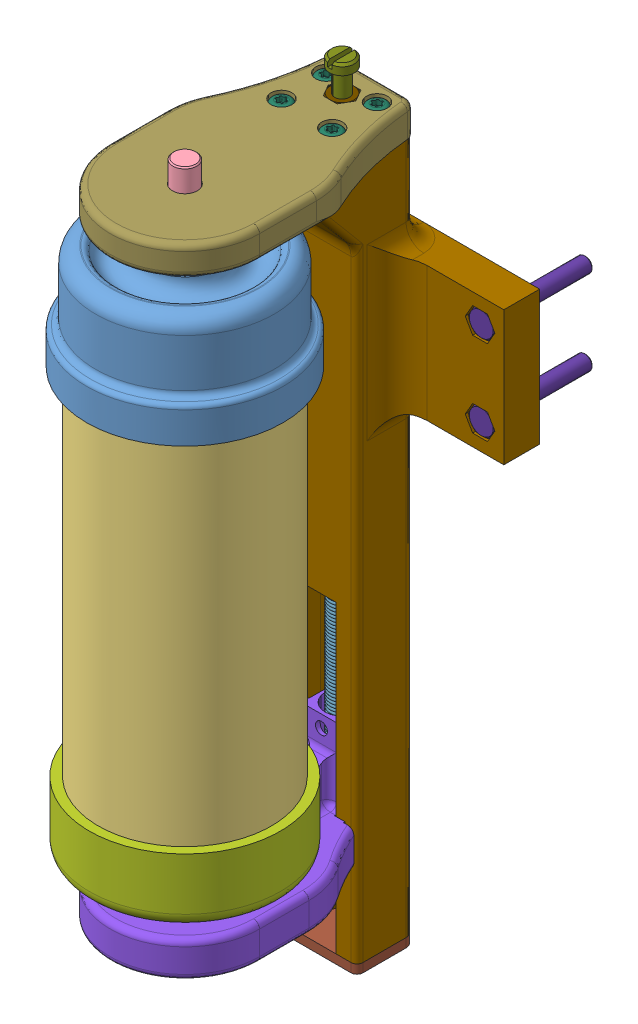
SolidWorks assembly AssemV-Chiller, configuration Default. Lengths in mm.
Overall size (100 255.81 129.09).
29 component instances, 18 part files, 65 mates.
Components (placement in the parent):
- Top holder of can-1: Top holder of can [Default] at (36.1197 55.3594 37.5996) x (-1 0 0) z (0 0 1) size (65.8 35 65.8)
- 250 ml CAN-1: 250 ml CAN [Default] at (36.1197 -108.6231 37.5996) x (0.908209 0 -0.418517) z (0.418517 0 0.908209) size (53.3 134.4 54.81)
- 330 ml CAN-1: 330 ml CAN [Default] at (36.1197 -101.7316 37.5996) x (0 0 1) z (-1 0 0) size (58 146 58)
- Screw M8x30-1: Screw M8x30 [Default] at (36.1197 60.7594 37.5996) x (-1 0 0) z (0 0 1) size (15.01 35.5 13)
- Washer M8_ISO 7090-1: Washer M8_ISO 7090 [Default] at (36.1197 60.7594 37.5996) x (0.773857 0 0.63336) z (-0.63336 0 0.773857) size (16 1.6 16)
- Screw nut M8-3: Screw nut M8 [Default] at (36.1197 66.9594 37.5996) x (0.505771 0 -0.862668) z (0 1 0) size (15.01 13 6.5)
- Washer M8_ISO 7090-3: Washer M8_ISO 7090 [Default] at (36.1197 66.9594 37.5996) x (0.994262 0 -0.106973) z (-0.106973 0 -0.994262) size (16 1.6 16)
- Bottom holder of can-1: Bottom holder of can [Default] at (36.1197 -110.6018 37.5996) x (0 0 -1) z (1 0 0) size (64 22 64)
- Screw M8x30-2: Screw M8x30 [Default] at (36.1197 -105.0018 37.5999) x (0.840809 0 -0.541331) z (0.541331 0 0.840809) size (15.01 35.5 13)
- Screw nut M8-4: Screw nut M8 [Default] at (36.1197 -118.7018 37.5999) x (0.505771 0 -0.862668) z (0 1 0) size (15.01 13 6.5)
- Washer M8_ISO 7090-4: Washer M8_ISO 7090 [Default] at (36.1197 -105.0018 37.5996) x (0.987196 0 -0.159509) z (-0.159509 0 -0.987196) size (16 1.6 16)
- Washer M8_ISO 7090-5: Washer M8_ISO 7090 [Default] at (36.1197 -110.6018 37.5999) x (0.987196 0 -0.159509) z (-0.159509 0 -0.987196) size (16 1.6 16)
- Spring holder_Bottom-1: Spring holder_Bottom [Default] at (36.1197 -130.5018 25.0999) x (0 0 1) z (0 1 0) size (84.36 50 42)
- Circular tube-1: Circular tube [Default] at (36.1197 -143.3406 -15.0604) size (100 231.6 45.4)
- Bearing 608-1: Bearing 608 [Default] at (36.1197 -122.2018 37.5999) x (0 1 0) z (0.985159 0 -0.171644) size (7 22 22)
- Screw nut M8-5: Screw nut M8 [Default] at (36.1197 -137.0018 37.5999) x (0.505771 0 -0.862668) z (0 1 0) size (15.01 13 6.5)
- Cover of circular tube bottom-1: Cover of circular tube bottom [Default] at (36.1197 -161.3406 -15.5604) x (0 0 -1) z (1 0 0) size (19.4 3 28.4)
- Holder of top bearing-1: Holder of top bearing [Default] at (36.1197 83.2594 25.0996) x (0 0 1) z (0 -1 0) size (87.86 50 10)
- Bearing 608-2: Bearing 608 [Default] at (36.1197 76.9594 37.5996) x (0 1 0) z (0.985159 0 -0.171644) size (7 22 22)
- 200 ml CAN-1: 200 ml CAN [Default] at (36.1197 -101.2229 37.5996) size (53.3 111.5 54.81)
- Tension spring-2: Tension spring [Default] at (36.1197 -103.0957 -14.702) x (1 0 0) z (0 1 0) size (8.62 9.93 100.8)
- 96817A522_THREAD-FORMING SCREW FOR THIN PLASTIC-1: 96817A522_THREAD-FORMING SCREW FOR THIN PLASTIC [96817A522] at (44.6197 79.8594 -18.2604) x (-0.165448 0 -0.986219) z (0 1 0) size (6.82 6.82 17.11)
- 96817A522_THREAD-FORMING SCREW FOR THIN PLASTIC-2: 96817A522_THREAD-FORMING SCREW FOR THIN PLASTIC [96817A522] at (44.6197 79.8594 -3.2604) x (0.912516 0 0.409041) z (0 1 0) size (6.82 6.82 17.11)
- 96817A522_THREAD-FORMING SCREW FOR THIN PLASTIC-3: 96817A522_THREAD-FORMING SCREW FOR THIN PLASTIC [96817A522] at (27.6197 79.8594 -3.2604) x (0.988371 0 0.152064) z (0 1 0) size (6.82 6.82 17.11)
- 96817A522_THREAD-FORMING SCREW FOR THIN PLASTIC-4: 96817A522_THREAD-FORMING SCREW FOR THIN PLASTIC [96817A522] at (27.6197 79.8594 -18.2604) x (1 0 0) z (0 1 0) size (6.82 6.82 17.11)
- Screw M5x50-1: Screw M5x50 [Default] at (36.1197 41.173 -15.0604) size (8.3 53.3 8.3)
- HEX screw M5X40-2: HEX screw M5X40 [Default] at (78.1545 34.9594 -23.2604) x (1 0 0) z (0 -1 0) size (9.24 35.1 8)
- HEX screw M5X40-3: HEX screw M5X40 [Default] at (78.1545 6.5594 -23.2604) x (1 0 0) z (0 -1 0) size (9.24 35.1 8)
- Nut M5-1: Nut M5 [Default] at (36.1197 79.2594 -15.0604) size (9.24 4 8)
Mates (geometry in assembly coordinates):
- Concentric1: concentric anti-aligned: cylinder of Top holder of can-1 through (36.1197 30.3594 37.5996) axis (0 1 0) radius 32.9; cylinder of 330 ml CAN-1 through (36.1197 -101.7316 37.5996) axis (0 -1 0) radius 29
- Concentric2: concentric anti-aligned: cylinder of Top holder of can-1 through (36.1197 30.3594 37.5996) axis (0 1 0) radius 32.9; cylinder of 250 ml CAN-1 through (36.1197 -108.6231 37.5996) axis (0 -1 0) radius 26.65
- Coincident1: coincident anti-aligned: plane of Top holder of can-1 through (36.1197 62.3594 37.5996) normal (0 -1 0); plane of Washer M8_ISO 7090-1 through (36.1197 62.3594 37.5996) normal (0 1 0)
- Concentric3: concentric aligned: cylinder of Top holder of can-1 through (36.1197 65.3594 37.5996) axis (0 -1 0) radius 4.1; cylinder of Washer M8_ISO 7090-1 through (36.1197 62.3594 37.5996) axis (0 -1 0) radius 4.2
- Coincident2: coincident anti-aligned: plane of Screw M8x30-1 through (36.1197 60.7594 37.5996) normal (0 1 0); plane of Washer M8_ISO 7090-1 through (36.1197 60.7594 37.5996) normal (0 -1 0)
- Concentric4: concentric aligned: cylinder of Top holder of can-1 through (36.1197 65.3594 37.5996) axis (0 -1 0) radius 4.1; cylinder of Screw M8x30-1 through (36.1197 90.7594 37.5996) axis (0 -1 0) radius 4
- Concentric5: concentric anti-aligned: cylinder of Screw M8x30-1 through (36.1197 90.7594 37.5996) axis (0 -1 0) radius 4; cylinder of Screw nut M8-3 through (36.1197 73.4594 37.5996) axis (0 1 0) radius 3.4
- Concentric61: concentric anti-aligned: cylinder of Screw M8x30-1 through (36.1197 90.7594 37.5996) axis (0 -1 0) radius 4; cylinder of Washer M8_ISO 7090-3 through (36.1197 65.3594 37.5996) axis (0 1 0) radius 4.2
- Coincident31: coincident anti-aligned: plane of Top holder of can-1 through (36.1197 65.3594 37.5996) normal (0 1 0); plane of Washer M8_ISO 7090-3 through (36.1197 65.3594 37.5996) normal (0 -1 0)
- Coincident71: coincident anti-aligned: plane of Screw M8x30-2 through (36.1197 -105.0018 37.5999) normal (0 -1 0); plane of Washer M8_ISO 7090-4 through (36.1197 -105.0018 37.5996) normal (0 1 0)
- Coincident81: coincident anti-aligned: plane of Bottom holder of can-1 through (36.1197 -110.6018 33.5996) normal (0 -1 0); plane of Washer M8_ISO 7090-5 through (36.1197 -110.6018 37.5999) normal (0 1 0)
- Concentric101: concentric aligned: cylinder of Screw M8x30-2 through (36.1197 -135.0018 37.5999) axis (0 1 0) radius 4; cylinder of Washer M8_ISO 7090-5 through (36.1197 -112.2018 37.5999) axis (0 1 0) radius 4.2
- Coincident91: coincident anti-aligned: plane of Screw nut M8-4 through (36.1197 -112.2018 37.5999) normal (0 1 0); plane of Washer M8_ISO 7090-5 through (36.1197 -112.2018 37.5999) normal (0 -1 0)
- Concentric111: concentric aligned: cylinder of Screw M8x30-2 through (36.1197 -135.0018 37.5999) axis (0 1 0) radius 4; cylinder of Screw nut M8-4 through (36.1197 -112.2018 37.5999) axis (0 1 0) radius 3.4
- Concentric141: concentric anti-aligned: cylinder of Top holder of can-1 through (36.1197 40.3594 37.5996) axis (0 1 0) radius 29.9; cylinder of Bottom holder of can-1 through (36.1197 -110.6018 37.5996) axis (0 -1 0) radius 32
- Concentric161: concentric anti-aligned: cylinder of Screw M8x30-2 through (36.1197 -135.0018 37.5999) axis (0 1 0) radius 4; cylinder of Spring holder_Bottom-1 through (36.1197 -118.5018 37.5999) axis (0 -1 0) radius 4.15
- Parallel11: parallel aligned: plane of Top holder of can-1 through (36.1197 55.3594 37.5996) normal (-1 0 0); plane of Circular tube-1 through (21.9197 -56.3406 -24.2604) normal (-1 0 0)
- Width1: width anti-aligned: plane of Circular tube-1 through (50.3197 -56.3406 -24.2604) normal (1 0 0); plane of Circular tube-1 through (21.9197 -56.3406 -24.2604) normal (-1 0 0); plane of Spring holder_Bottom-1 through (25.9651 -118.5018 -14.81) normal (-1 0 0); plane of Spring holder_Bottom-1 through (46.2742 -118.5018 -22.4001) normal (1 0 0)
- Concentric162: concentric anti-aligned: cylinder of Screw M8x30-2 through (36.1197 -135.0018 37.5999) axis (0 1 0) radius 4; cylinder of Bearing 608-1 through (36.1197 -122.2018 37.5999) axis (0 -1 0) radius 4
- Coincident102: coincident anti-aligned: plane of Spring holder_Bottom-1 through (36.1197 -125.7018 37.5999) normal (0 1 0); plane of Bearing 608-1 through (38.0078 -125.7018 48.4366) normal (0 -1 0)
- Coincident103: coincident anti-aligned: plane of Screw nut M8-4 through (36.1197 -118.7018 37.5999) normal (0 -1 0); plane of Bearing 608-1 through (38.0078 -118.7018 48.4366) normal (0 1 0)
- Concentric163: concentric aligned: cylinder of Screw M8x30-2 through (36.1197 -135.0018 37.5999) axis (0 1 0) radius 4; cylinder of Screw nut M8-5 through (36.1197 -130.5018 37.5999) axis (0 1 0) radius 3.4
- Coincident104: coincident anti-aligned: plane of Spring holder_Bottom-1 through (-45.9663 -130.5018 -36.0437) normal (0 -1 0); plane of Screw nut M8-5 through (36.1197 -130.5018 37.5999) normal (0 1 0)
- Concentric164: concentric aligned: cylinder of Spring holder_Bottom-1 through (36.1197 -103.5018 -15.0604) axis (0 -1 0) radius 6.7; cylinder of Circular tube-1 through (36.1197 -56.3406 -15.0604) axis (0 -1 0) radius 7.2
- Coincident105: coincident aligned: plane of Circular tube-1 through (36.1197 -143.214 -15.0606) normal (1 0 0); plane of ? through (36.1197 -143.214 -14.982) normal (1 0 0)
- Coincident106: coincident anti-aligned: plane of Circular tube-1 through (36.1197 -143.214 -15.0606) normal (0 -1 0); plane of ? through (36.1197 -143.214 -14.982) normal (0 1 0)
- Lock1: lock: unknown of Circular tube-1; unknown of ?
- Coincident107: coincident aligned: plane of Circular tube-1 through (36.1197 -143.3406 -25.2604) normal (0 0 -1); plane of Cover of circular tube bottom-1 through (21.9197 -158.3406 -25.2604) normal (0 0 -1)
- Coincident108: coincident aligned: plane of Circular tube-1 through (21.9197 -56.3406 -24.2604) normal (-1 0 0); plane of Cover of circular tube bottom-1 through (21.9197 -158.3406 -25.2604) normal (-1 0 0)
- Concentric165: concentric anti-aligned: cylinder of Screw M8x30-1 through (36.1197 90.7594 37.5996) axis (0 -1 0) radius 4; cylinder of Holder of top bearing-1 through (36.1197 73.2594 37.5996) axis (0 1 0) radius 4.15
- Coincident112: coincident anti-aligned: plane of Holder of top bearing-1 through (36.1197 80.4594 37.5996) normal (0 -1 0); plane of Bearing 608-2 through (38.0078 80.4594 48.4364) normal (0 1 0)
- Concentric166: concentric aligned: cylinder of Holder of top bearing-1 through (36.1197 80.4594 37.5996) axis (0 -1 0) radius 11; cylinder of Bearing 608-2 through (36.1197 76.9594 37.5996) axis (0 -1 0) radius 11
- Coincident113: coincident anti-aligned: plane of Screw nut M8-3 through (36.1197 73.4594 37.5996) normal (0 1 0); plane of Bearing 608-2 through (38.0078 73.4594 48.4364) normal (0 -1 0)
- Coincident114: coincident anti-aligned: plane of Screw nut M8-3 through (36.1197 66.9594 37.5996) normal (0 -1 0); plane of Washer M8_ISO 7090-3 through (36.1197 66.9594 37.5996) normal (0 1 0)
- Parallel14: parallel anti-aligned: plane of Top holder of can-1 through (36.1197 55.3594 37.5996) normal (0 0 1); plane of Bottom holder of can-1 through (36.1197 -110.6018 37.5996) normal (0 0 -1)
- Concentric167: concentric anti-aligned: cylinder of Top holder of can-1 through (36.1197 30.3594 37.5996) axis (0 1 0) radius 32.9; cylinder of 200 ml CAN-1 through (36.1197 -101.2229 37.5996) axis (0 -1 0) radius 26.65
- Parallel15: parallel aligned: plane of Circular tube-1 through (50.3197 -56.3406 -5.8604) normal (0 0 1); plane of 200 ml CAN-1 through (36.1197 -101.2229 37.5996) normal (0 0 1)
- Parallel16: parallel anti-aligned: plane of 330 ml CAN-1 through (36.1197 -101.7316 37.5996) normal (0 0 1); plane of Circular tube-1 through (36.1197 -143.3406 -25.2604) normal (0 0 -1)
- Coincident115: coincident anti-aligned: plane of Holder of top bearing-1 through (140.1716 83.2594 -30.4212) normal (0 1 0); plane of ? through (21.1086 84.2971 39.2893) normal (0 -1 0)
- Concentric168: concentric aligned: cylinder of Screw M8x30-1 through (36.1197 90.7594 37.5996) axis (0 -1 0) radius 4; cylinder of ? through (36.1197 83.2594 37.5996) axis (0 -1 0) radius 3.4
- Parallel17: parallel anti-aligned: plane of Circular tube-1 through (21.9197 -56.3406 -24.2604) normal (-1 0 0); plane of Tension spring-2 through (36.1197 -103.0957 -14.702) normal (1 0 0)
- Symmetric1: symmetric aligned: plane of Circular tube-1 through (21.9197 -56.3406 -24.2604) normal (-1 0 0); plane of Circular tube-1 through (50.3197 -56.3406 -24.2604) normal (1 0 0); plane of Tension spring-2 through (36.1197 -103.0957 -14.702) normal (1 0 0)
- Coincident118: coincident aligned: plane of Circular tube-1 through (36.1197 -143.3406 -25.2604) normal (0 0 -1); plane of Holder of top bearing-1 through (21.9197 73.2594 -25.2604) normal (0 0 -1)
- Coincident120: coincident aligned: plane of Circular tube-1 through (36.1197 -143.3406 -15.0604) normal (1 0 0); plane of Screw M5x50-1 through (36.1197 41.173 -15.0604) normal (1 0 0)
- Coincident121: coincident aligned: plane of Circular tube-1 through (36.1197 -143.3406 -15.0604) normal (0 0 1); plane of Screw M5x50-1 through (36.1197 41.173 -15.0604) normal (0 0 1)
- Coincident122: coincident anti-aligned: plane of Holder of top bearing-1 through (34.0989 79.7594 -11.5606) normal (0 0 -1); plane of ? through (34.0989 82.9594 -11.5606) normal (0 0 1)
- Coincident126: coincident anti-aligned: plane of Holder of top bearing-1 through (38.1404 79.7594 -11.5606) normal (-0.866025 0 -0.5); plane of ? through (38.1404 82.9594 -11.5606) normal (0.866025 0 0.5)
- Coincident127: coincident anti-aligned: plane of Holder of top bearing-1 through (36.1197 79.7594 25.0996) normal (0 1 0); plane of ? through (36.1197 79.7594 -15.0606) normal (0 -1 0)
- Concentric170: concentric anti-aligned: cylinder of Holder of top bearing-1 through (27.6197 73.2594 -18.2604) axis (0 1 0) radius 1.5; cylinder of 96817A522_THREAD-FORMING SCREW FOR THIN PLASTIC-4 through (27.6197 82.9594 -18.2604) axis (0 -1 0) radius 3.41
- Concentric171: concentric anti-aligned: cylinder of Holder of top bearing-1 through (27.6197 73.2594 -3.2604) axis (0 1 0) radius 1.5; cylinder of 96817A522_THREAD-FORMING SCREW FOR THIN PLASTIC-3 through (27.6197 82.9594 -3.2604) axis (0 -1 0) radius 3.41
- Concentric172: concentric anti-aligned: cylinder of Holder of top bearing-1 through (44.6197 73.2594 -3.2604) axis (0 1 0) radius 1.5; cylinder of 96817A522_THREAD-FORMING SCREW FOR THIN PLASTIC-2 through (44.6197 82.9594 -3.2604) axis (0 -1 0) radius 3.41
- Concentric173: concentric anti-aligned: cylinder of Holder of top bearing-1 through (44.6197 73.2594 -18.2604) axis (0 1 0) radius 1.5; cylinder of 96817A522_THREAD-FORMING SCREW FOR THIN PLASTIC-1 through (44.6197 82.9594 -18.2604) axis (0 -1 0) radius 3.41
- Coincident128: coincident anti-aligned: plane of Holder of top bearing-1 through (44.6197 79.8594 -18.2604) normal (0 1 0); plane of 96817A522_THREAD-FORMING SCREW FOR THIN PLASTIC-1 through (44.6197 79.8594 -18.2604) normal (0 -1 0)
- Coincident129: coincident anti-aligned: plane of Holder of top bearing-1 through (27.6197 79.8594 -18.2604) normal (0 1 0); plane of 96817A522_THREAD-FORMING SCREW FOR THIN PLASTIC-4 through (27.6197 79.8594 -18.2604) normal (0 -1 0)
- Coincident130: coincident anti-aligned: plane of Holder of top bearing-1 through (44.6197 79.8594 -3.2604) normal (0 1 0); plane of 96817A522_THREAD-FORMING SCREW FOR THIN PLASTIC-2 through (44.6197 79.8594 -3.2604) normal (0 -1 0)
- Coincident131: coincident anti-aligned: plane of Holder of top bearing-1 through (27.6197 79.8594 -3.2604) normal (0 1 0); plane of 96817A522_THREAD-FORMING SCREW FOR THIN PLASTIC-3 through (27.6197 79.8594 -3.2604) normal (0 -1 0)
- Concentric174: concentric aligned: cylinder of Circular tube-1 through (78.1545 34.9594 -31.2604) axis (0 0 1) radius 2.75; cylinder of HEX screw M5X40-2 through (78.1545 34.9594 -54.7604) axis (0 0 1) radius 2.5
- Coincident133: coincident anti-aligned: plane of Circular tube-1 through (36.1197 -143.3406 -23.2604) normal (0 0 1); plane of HEX screw M5X40-2 through (78.1545 34.9594 -23.2604) normal (0 0 -1)
- Coincident135: coincident anti-aligned: plane of Circular tube-1 through (36.1197 -143.3406 -23.2604) normal (0 0 1); plane of HEX screw M5X40-3 through (78.1545 6.5594 -23.2604) normal (0 0 -1)
- Concentric176: concentric aligned: cylinder of Circular tube-1 through (78.1545 6.5594 -31.2604) axis (0 0 1) radius 2.75; cylinder of HEX screw M5X40-3 through (78.1545 6.5594 -54.7604) axis (0 0 1) radius 2.5
- Coincident137: coincident anti-aligned: plane of Holder of top bearing-1 through (36.1197 79.2594 25.0996) normal (0 1 0); plane of Nut M5-1 through (36.1197 79.2594 -15.0604) normal (0 -1 0)
- Concentric177: concentric anti-aligned: cylinder of Screw M5x50-1 through (36.1197 41.173 -15.0604) axis (0 -1 0) radius 2.5; cylinder of Nut M5-1 through (36.1197 83.2594 -15.0604) axis (0 1 0) radius 2.1
- Coincident138: coincident anti-aligned: plane of Circular tube-1 through (36.1197 73.2594 -15.0604) normal (0 1 0); plane of Holder of top bearing-1 through (140.1716 73.2594 -30.4212) normal (0 -1 0)
- Coincident139: coincident aligned: plane of Circular tube-1 through (36.1197 -143.3406 -25.2604) normal (0 0 -1); plane of Holder of top bearing-1 through (21.9197 73.2594 -25.2604) normal (0 0 -1)
- Coincident141: coincident anti-aligned: plane of Circular tube-1 through (47.3197 -158.3406 -22.2604) normal (0 -1 0); plane of Cover of circular tube bottom-1 through (36.1197 -158.3406 -15.5604) normal (0 1 0)
